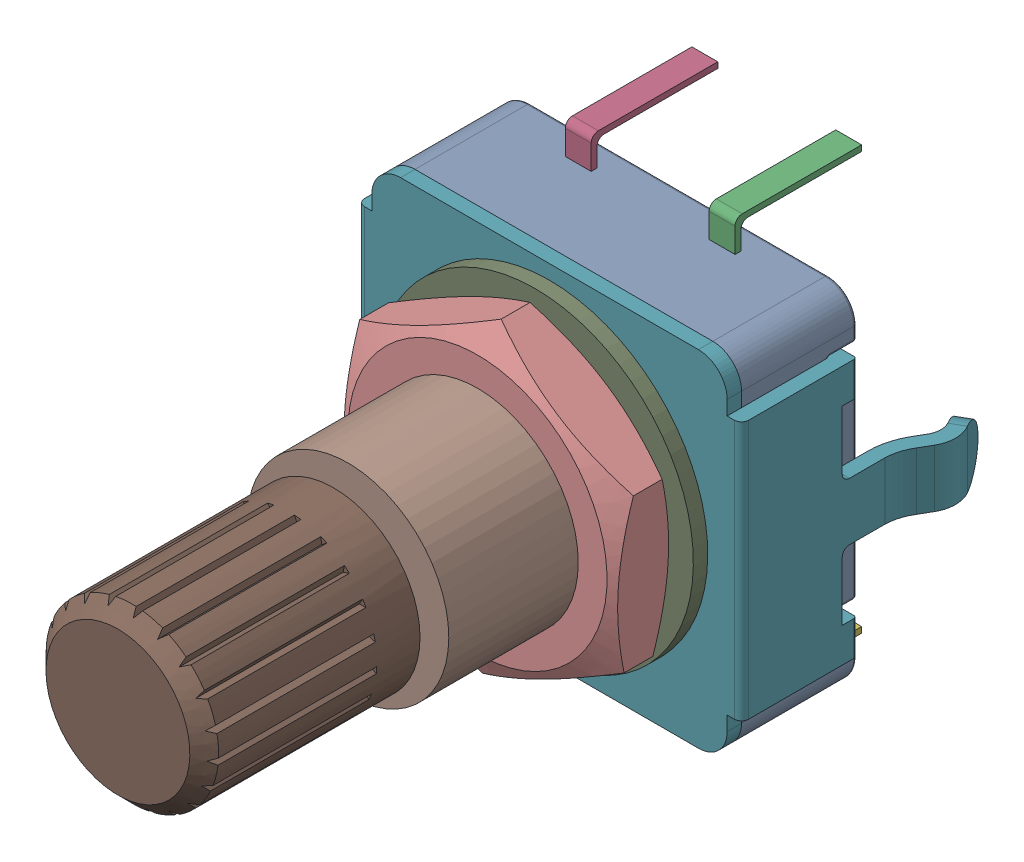
SolidWorks assembly PEC11_4220_S0024, configuration Default. Lengths in mm.
Overall size (14.62 14.7 23.24).
11 component instances, 7 part files, 0 mates.
Components (placement in the parent):
- 12mm_Incremental_Encoder_Base_1-1: 12mm_Incremental_Encoder_Base_1 [Default] at origin size (12.36 12 4)
- 12mm_Incremental_Encoder_Pin_1-1: 12mm_Incremental_Encoder_Pin_1 [Default] at (0 -6.6 0.8) x (0 -1 0) z (-1 0 0) size (3 4.4 0.9)
- 12mm_Incremental_Encoder_Pin_1-2: 12mm_Incremental_Encoder_Pin_1 [Default] at (2.5 6.1 0.8) x (0 1 0) z (1 0 0) size (3 4.4 0.9)
- 12mm_Incremental_Encoder_Pin_1-3: 12mm_Incremental_Encoder_Pin_1 [Default] at (-2.5 6.1 0.8) x (0 1 0) z (1 0 0) size (3 4.4 0.9)
- 12mm_Incremental_Encoder_Pin_1-4: 12mm_Incremental_Encoder_Pin_1 [Default] at (-2.5 -6.6 0.8) x (0 -1 0) z (-1 0 0) size (3 4.4 0.9)
- 12mm_Incremental_Encoder_Pin_1-5: 12mm_Incremental_Encoder_Pin_1 [Default] at (2.5 -6.6 0.8) x (0 -1 0) z (-1 0 0) size (3 4.4 0.9)
- 12mm_Incremental_Encoder_Anti-Rotation_Plate_1-1: 12mm_Incremental_Encoder_Anti-Rotation_Plate_1 [Default] at (0 0 4) size (14.62 12 8.24)
- 12mm_Incremental_Encoder_Threaded_Tube_1-1: 12mm_Incremental_Encoder_Threaded_Tube_1 [Default] at (-5.8861 -2.5756 11.5) x (-0.916131 -0.400879 0) z (0 0 -1) size (7 7 7)
- 12mm_Incremental_Encoder_Washer_1-1: 12mm_Incremental_Encoder_Washer_1 [Default] at (6.424 -0.1143 4.5) x (0.999842 -0.017794 0) z (0 0 1) size (11 11 0.5)
- M7x0.75_Hex_Nut_1-1: M7x0.75_Hex_Nut_1 [Default] at (0 0 5) x (0.835271 -0.549838 0) z (0 0 1) size (11 9.53 2)
- 12mm_Incremental_Encoder_Shaft-1: 12mm_Incremental_Encoder_Shaft [Default] at (0 0 11.5) x (0.652489 0.757799 0) z (0 0 1) size (6 6 13)
